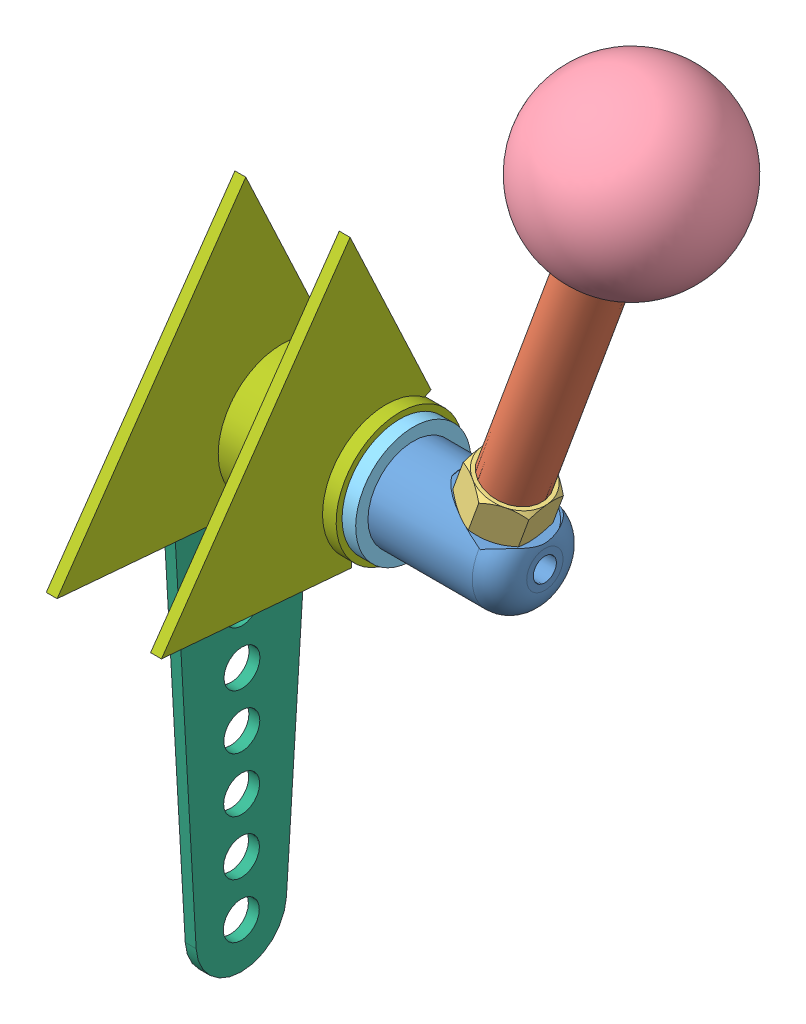
SolidWorks assembly ShifterAssembly, configuration Default. Lengths in mm.
Overall size (121.21 223.19 81.79).
8 component instances, 7 part files, 15 mates.
Components (placement in the parent):
- ShifterShaft-1: ShifterShaft [Default] at (-3.2 0 0) x (1 0 0) z (0 0.003165 0.999995) size (69.49 24.49 20)
- ShifterLever-1: ShifterLever [Default] at (65.9622 33.4151 -0.1057) x (0.34202 0.939688 -0.002974) z (0.932407 -0.338973 0.125356) size (95 12.7 12.7)
- Hex Nut_AI-1: Hex Nut_AI [HNUT 0.3750-16-D-N] at (56.1941 6.5778 -0.0208) x (0.93685 -0.34123 -0.076638) z (-0.34202 -0.939688 0.002974) size (14.27 16.48 8.56)
- ShifterBall-1: ShifterBall [Default] at (84.6372 84.7242 -0.2681) x (0.702729 -0.257872 -0.663079) z (0.623854 -0.224697 0.748543) size (40 39.6 40)
- ShifterBush-1: ShifterBush [Default] at (33.8 0 0) x (1 0 0) z (0 0.498744 0.866749) size (18 25.4 25.4)
- ShifterBush-2: ShifterBush [Default] at (2.4 0 0) x (-1 0 0) z (0 -0.816676 -0.577097) size (18 25.4 25.4)
- ShifterOuterLever-1: ShifterOuterLever [Default] at (-3.2 0 0) x (0 -0.999995 0.003165) z (0 0.003165 0.999995) size (125.97 2.4 32)
- ShifterBracket-1: ShifterBracket [Default] at (18.1 0 0) x (0 -0.820462 0.571701) z (1 0 0) size (72.75 49 31.4)
Mates (geometry in assembly coordinates):
- Concentric1: concentric: cylinder of assembly; cylinder of assembly; cylinder of ShifterShaft-1 through (58.4177 12.6869 -0.0401) axis (-0.34202 -0.939688 0.002974) radius 4.2164; cylinder of ShifterLever-1 through (59.1218 14.6214 -0.0463) axis (-0.34202 -0.939688 0.002974) radius 4.7625
- Concentric2: concentric: cylinder of assembly; cylinder of assembly; cylinder of ShifterLever-1 through (59.1218 14.6214 -0.0463) axis (-0.34202 -0.939688 0.002974) radius 4.7625; cylinder of Hex Nut_AI-1 through (64.7575 30.1053 -0.0953) axis (-0.34202 -0.939688 0.002974) radius 4.7625
- Coincident1: coincident: plane of assembly; plane of assembly; plane of ShifterLever-1 through (59.1218 14.6214 -0.0463) normal (-0.34202 -0.939688 0.002974); plane of Hex Nut_AI-1 through (45.7484 19.4923 1.0477) normal (0.34202 0.939688 -0.002974)
- Coincident3: coincident: plane of assembly; plane of assembly; plane of ShifterShaft-1 through (56.1941 6.5778 -0.0208) normal (0.34202 0.939688 -0.002974); plane of Hex Nut_AI-1 through (42.8208 11.4488 1.0732) normal (-0.34202 -0.939688 0.002974)
- Concentric4: concentric: cylinder of assembly; cylinder of assembly; cylinder of ShifterLever-1 through (77.9329 66.3042 -0.2098) axis (0.34202 0.939688 -0.002974) radius 4.7625; cylinder of ShifterBall-1 through (85.6633 87.5433 -0.277) axis (0.34202 0.939688 -0.002974) radius 3.9688
- Coincident4: coincident: plane of assembly; circle of assembly; plane of ShifterLever-1 through (77.9329 66.3042 -0.2098) normal (0.34202 0.939688 -0.002974); circle of ShifterBall-1
- Concentric5: concentric: cylinder of assembly; cylinder of assembly; cylinder of ShifterShaft-1 through (36.8 0 0) axis (-1 0 0) radius 9; cylinder of ShifterBush-1 through (-59.7891 0 0) axis (-1 0 0) radius 9
- Coincident5: coincident: plane of ShifterShaft-1 through (36.8 0 0) normal (-1 0 0); plane of ShifterBush-1 through (36.8 -4.4887 -7.8007) normal (1 0 0)
- Concentric6: concentric: cylinder of assembly; cylinder of assembly; cylinder of ShifterShaft-1 through (36.8 0 0) axis (-1 0 0) radius 9; cylinder of ShifterBush-2 through (95.9891 0 0) axis (1 0 0) radius 9
- Coincident7: coincident: plane of assembly; plane of assembly; plane of ShifterShaft-1 through (-0.8 6.9778 -7.0221) normal (0 0.999995 -0.003165); plane of ShifterOuterLever-1 through (-0.8 6.9829 -5.4221) normal (0 -0.999995 0.003165)
- Coincident8: coincident: plane of ShifterShaft-1 through (-0.8 -6.9778 7.0221) normal (0 0.003165 0.999995); plane of ShifterOuterLever-1 through (-0.8 5.4221 6.9829) normal (0 -0.003165 -0.999995)
- Coincident9: coincident: plane of ShifterShaft-1 through (-3.2 0 0) normal (-1 0 0); plane of ShifterOuterLever-1 through (-3.2 0 0) normal (-1 0 0)
- Concentric7: concentric: cylinder of ShifterBush-1 through (-59.7891 0 0) axis (-1 0 0) radius 11; cylinder of ShifterBracket-1 through (2.4 0 0) axis (1 0 0) radius 11
- Coincident10: coincident: plane of ShifterBush-2 through (2.4 10.3718 7.3291) normal (1 0 0); plane of ShifterBracket-1 through (2.4 0 0) normal (-1 0 0)
- Coincident11: coincident: plane of ShifterBush-1 through (33.8 -6.334 -11.0077) normal (-1 0 0); plane of ShifterBracket-1 through (33.8 0 0) normal (1 0 0)
